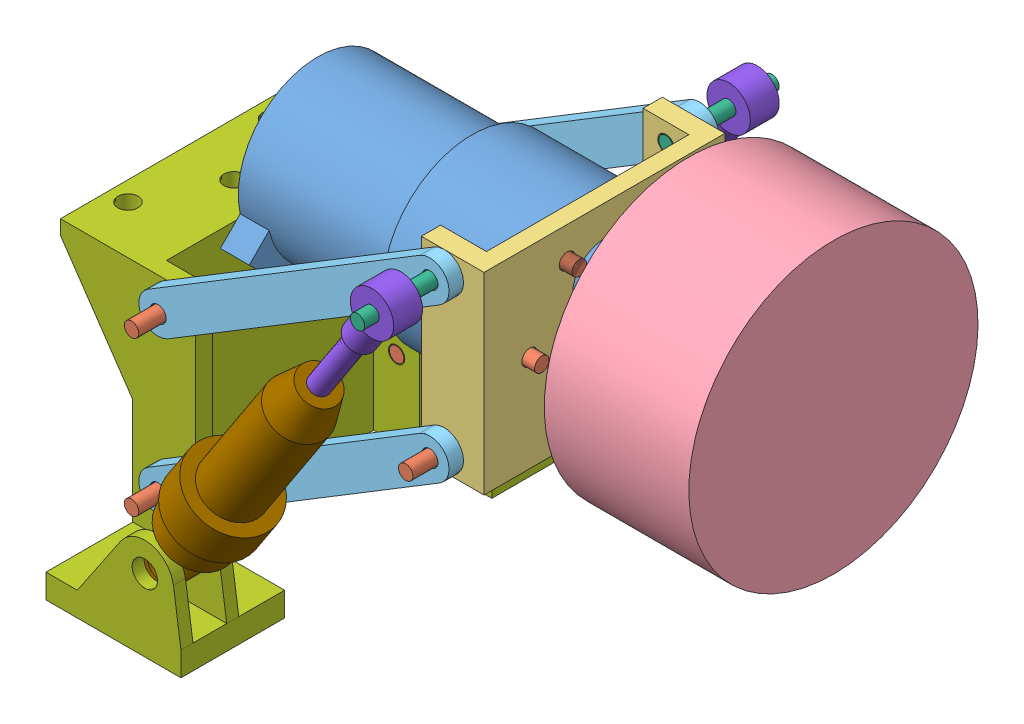
SolidWorks assembly 悬挂, configuration 默认. Lengths in mm.
Overall size (135.39 111.77 91).
29 component instances, 9 part files, 55 mates.
Components (placement in the parent):
- 37mm电机简化-1: 37mm电机简化 [默认] at (-59.3265 -45.8571 59.5689) size (74 38.77 38.72)
- M3-12螺丝简化-1: M3-12螺丝简化 [默认] at (-29.3265 -32.4337 67.3189) x (0 -0.670564 0.741852) z (-1 0 0) size (3 3 12)
- 双叉连接-1: 双叉连接 [默认] at (-36.8265 -45.8571 59.5689) x (0 0 1) z (1 0 0) size (50 40 13)
- 麦轮简化-1: 麦轮简化 [默认] at (15.6735 -38.8571 59.5689) x (0 0.939245 -0.343247) z (0 0.343247 0.939245) size (60 45 60)
- 双叉连杆-1: 双叉连杆 [默认] at (-68.2713 -79.0051 34.5689) x (0.854387 0.519637 0) z (-0.519637 0.854387 0) size (74 3 8)
- M3-12螺丝简化-17: M3-12螺丝简化 [默认] at (-41.3265 -59.2805 51.8189) x (0 0 -1) z (1 0 0) size (3 3 12)
- M3-12螺丝简化-18: M3-12螺丝简化 [默认] at (-41.3265 -32.4337 51.8189) x (0 0 -1) z (1 0 0) size (3 3 12)
- M3-12螺丝简化-19: M3-12螺丝简化 [默认] at (-41.3265 -45.8571 44.0689) x (0 0 -1) z (1 0 0) size (3 3 12)
- M3-12螺丝简化-20: M3-12螺丝简化 [默认] at (-41.3265 -45.8571 75.0689) x (0 0 -1) z (1 0 0) size (3 3 12)
- M3-12螺丝简化-21: M3-12螺丝简化 [默认] at (-41.3265 -32.4337 67.3189) x (0 0 -1) z (1 0 0) size (3 3 12)
- 双叉连杆-2: 双叉连杆 [默认] at (-68.2713 -79.0051 87.5689) x (0.854387 0.519637 0) z (-0.519637 0.854387 0) size (74 3 8)
- 双叉连杆-3: 双叉连杆 [默认] at (-68.2713 -47.0051 87.5689) x (0.854387 0.519637 0) z (-0.519637 0.854387 0) size (74 3 8)
- 双叉连杆-4: 双叉连杆 [默认] at (-68.2713 -47.0051 34.5689) x (0.854387 0.519637 0) z (-0.519637 0.854387 0) size (74 3 8)
- M3-12螺丝简化-23: M3-12螺丝简化 [默认] at (-40.0765 -61.8571 26.5689) x (0.912289 -0.409547 0) z (0 0 1) size (3 3 12)
- M3-12螺丝简化-24: M3-12螺丝简化 [默认] at (-40.0765 -61.8571 80.5689) size (3 3 12)
- M3-12螺丝简化-27: M3-12螺丝简化 [默认] at (-29.3265 -59.2805 67.3189) x (0 0 1) z (-1 0 0) size (3 3 12)
- M3-16螺丝简化-1: M3-16螺丝简化 [默认] at (-40.0765 -29.8571 16.5689) size (3 3 22)
- M3-16螺丝简化-2: M3-16螺丝简化 [默认] at (-40.0765 -29.8571 80.5689) x (0.99844 -0.055842 0) z (0 0 1) size (3 3 22)
- 弹簧支架-1: 弹簧支架 [默认] at (-99.716 -80.1532 59.5689) x (0 0 1) z (-1 0 0) size (86 52 43)
- M3-12螺丝简化-28: M3-12螺丝简化 [默认] at (-96.466 -64.1532 26.0689) size (3 3 12)
- M3-12螺丝简化-29: M3-12螺丝简化 [默认] at (-96.466 -96.1532 26.0689) size (3 3 12)
- M3-12螺丝简化-30: M3-12螺丝简化 [默认] at (-96.466 -96.1532 81.0689) size (3 3 12)
- M3-12螺丝简化-31: M3-12螺丝简化 [默认] at (-96.466 -64.1532 81.0689) size (3 3 12)
- 避震器简化-1: 避震器简化 [默认] at (55.1031 -55.4246 67.9345) size (59.67 81.53 17) (flexible)
  - 避震器简化-1: 避震器简化 [默认] at (-106.1486 8.8438 -45.3656) x (0 0 1) z (-0.836182 0.548453 0) size (6 39.5 9)
  - 避震器下简化-1: 避震器下简化 [默认] at (-103.6697 12.6232 -45.3656) x (0 0 1) z (-0.836182 0.548453 0) size (17 59 17)
- 避震器简化-2: 避震器简化 [默认] at (55.1031 -55.4246 141.9345) size (59.67 81.53 17) (flexible)
  - 避震器简化-1: 避震器简化 [默认] at (-106.1486 8.8438 -45.3656) x (0 0 1) z (-0.836182 0.548453 0) size (6 39.5 9)
  - 避震器下简化-1: 避震器下简化 [默认] at (-103.6697 12.6232 -45.3656) x (0 0 1) z (-0.836182 0.548453 0) size (17 59 17)
Mates (geometry in assembly coordinates):
- 同心1: concentric anti-aligned: circle of 37mm电机简化-1; circle of 双叉连接-1
- 同心2: concentric anti-aligned: circle of 37mm电机简化-1; circle of 双叉连接-1
- 同心3: concentric anti-aligned: circle of 37mm电机简化-1; circle of M3-12螺丝简化-1
- 重合3: coincident anti-aligned: plane of 37mm电机简化-1 through (-41.3265 -32.4337 67.3189) normal (1 0 0); plane of M3-12螺丝简化-1 through (-41.3265 -32.4337 67.3189) normal (-1 0 0)
- 重合18: coincident anti-aligned: plane of 37mm电机简化-1 through (-41.3265 -32.4337 51.8189) normal (1 0 0); plane of M3-12螺丝简化-17 through (-41.3265 -59.2805 51.8189) normal (-1 0 0)
- 同心9: concentric anti-aligned: circle of 双叉连接-1; circle of M3-12螺丝简化-17
- 重合19: coincident anti-aligned: plane of 37mm电机简化-1 through (-41.3265 -45.8571 75.0689) normal (1 0 0); plane of M3-12螺丝简化-21 through (-41.3265 -32.4337 67.3189) normal (-1 0 0)
- 重合20: coincident anti-aligned: plane of 37mm电机简化-1 through (-41.3265 -59.2805 67.3189) normal (1 0 0); plane of M3-12螺丝简化-21 through (-41.3265 -32.4337 67.3189) normal (-1 0 0)
- 重合22: coincident aligned: plane of M3-12螺丝简化-18 through (-41.3265 -32.4337 51.8189) normal (-1 0 0); plane of M3-12螺丝简化-19 through (-41.3265 -45.8571 44.0689) normal (-1 0 0)
- 重合24: coincident aligned: plane of M3-12螺丝简化-19 through (-41.3265 -45.8571 44.0689) normal (-1 0 0); plane of M3-12螺丝简化-20 through (-41.3265 -45.8571 75.0689) normal (-1 0 0)
- 重合25: coincident anti-aligned: plane of 37mm电机简化-1 through (-41.3265 -45.8571 75.0689) normal (1 0 0); plane of M3-12螺丝简化-18 through (-41.3265 -32.4337 51.8189) normal (-1 0 0)
- 同心10: concentric anti-aligned: circle of 双叉连接-1; circle of M3-12螺丝简化-20
- 同心11: concentric anti-aligned: circle of 双叉连接-1; circle of M3-12螺丝简化-19
- 同心12: concentric anti-aligned: circle of 双叉连接-1; circle of M3-12螺丝简化-18
- 同心13: concentric anti-aligned: circle of 双叉连接-1; circle of M3-12螺丝简化-21
- 同心15: concentric anti-aligned: circle of 37mm电机简化-1; circle of 麦轮简化-1
- 重合30: coincident anti-aligned: plane of 37mm电机简化-1 through (-29.3265 -38.8571 59.5689) normal (1 0 0); plane of 麦轮简化-1 through (-29.3265 -38.8571 59.5689) normal (-1 0 0)
- 重合31: coincident anti-aligned: plane of 双叉连接-1 through (-31.8265 -65.8571 34.5689) normal (0 0 -1); plane of 双叉连杆-1 through (-96.466 -96.1532 34.5689) normal (0 0 1)
- 同心19: concentric anti-aligned: circle of 双叉连接-1; circle of 双叉连杆-1
- 同心20: concentric anti-aligned: circle of 双叉连杆-1; circle of M3-12螺丝简化-23
- 同心21: concentric anti-aligned: circle of 双叉连接-1; circle of 双叉连杆-4
- 重合38: coincident anti-aligned: plane of 双叉连接-1 through (-31.8265 -65.8571 34.5689) normal (0 0 -1); plane of 双叉连杆-4 through (-96.466 -64.1532 34.5689) normal (0 0 1)
- 重合40: coincident aligned: plane of 双叉连杆-2 through (-96.466 -96.1532 84.5689) normal (0 0 -1); plane of 双叉连杆-3 through (-96.466 -64.1532 84.5689) normal (0 0 -1)
- 重合41: coincident anti-aligned: plane of 双叉连接-1 through (-31.8265 -65.8571 84.5689) normal (0 0 1); plane of 双叉连杆-3 through (-96.466 -64.1532 84.5689) normal (0 0 -1)
- 同心23: concentric anti-aligned: circle of 双叉连接-1; circle of 双叉连杆-3
- 同心24: concentric anti-aligned: circle of 双叉连接-1; circle of 双叉连杆-2
- 同心25: concentric anti-aligned: circle of 双叉连杆-2; circle of M3-12螺丝简化-24
- 重合46: coincident anti-aligned: plane of 37mm电机简化-1 through (-35.3265 -45.8571 59.5689) normal (1 0 0); plane of 双叉连接-1 through (-35.3265 -45.8571 59.5689) normal (-1 0 0)
- 重合47: coincident anti-aligned: circle of 37mm电机简化-1; circle of M3-12螺丝简化-27
- 同心27: concentric aligned: circle of 双叉连接-1; circle of M3-12螺丝简化-27
- 同心28: concentric anti-aligned: circle of 双叉连杆-3; circle of M3-16螺丝简化-2
- 同心29: concentric anti-aligned: circle of 双叉连杆-4; circle of M3-16螺丝简化-1
- 重合52: coincident aligned: plane of 双叉连接-1 through (-44.8265 -65.8571 80.5689) normal (0 0 -1); plane of M3-12螺丝简化-24 through (-40.0765 -61.8571 80.5689) normal (0 0 -1)
- 重合53: coincident aligned: plane of 双叉连接-1 through (-35.3265 -65.8571 38.5689) normal (0 0 1); plane of M3-12螺丝简化-23 through (-40.0765 -61.8571 38.5689) normal (0 0 1)
- 重合54: coincident aligned: plane of 双叉连接-1 through (-35.3265 -65.8571 38.5689) normal (0 0 1); plane of M3-16螺丝简化-1 through (-40.0765 -29.8571 38.5689) normal (0 0 1)
- 重合55: coincident aligned: plane of 双叉连接-1 through (-44.8265 -65.8571 80.5689) normal (0 0 -1); plane of M3-16螺丝简化-2 through (-40.0765 -29.8571 80.5689) normal (0 0 -1)
- 重合56: coincident anti-aligned: plane of 双叉连杆-4 through (-96.466 -64.1532 34.5689) normal (0 0 1); plane of 弹簧支架-1 through (-104.716 -60.1532 34.5689) normal (0 0 -1)
- 同心31: concentric anti-aligned: circle of 双叉连杆-4; circle of 弹簧支架-1
- 同心32: concentric anti-aligned: circle of 双叉连杆-1; circle of 弹簧支架-1
- 同心33: concentric anti-aligned: circle of 双叉连杆-2; circle of 弹簧支架-1
- 同心34: concentric anti-aligned: circle of 双叉连杆-3; circle of 弹簧支架-1
- 同心35: concentric anti-aligned: circle of 双叉连杆-3; circle of M3-12螺丝简化-31
- 重合62: coincident anti-aligned: plane of 弹簧支架-1 through (-91.716 -60.1532 81.0689) normal (0 0 -1); circle of M3-12螺丝简化-31
- 同心36: concentric anti-aligned: circle of 双叉连杆-2; circle of M3-12螺丝简化-30
- 重合63: coincident anti-aligned: plane of 弹簧支架-1 through (-91.716 -60.1532 81.0689) normal (0 0 -1); circle of M3-12螺丝简化-30
- 同心37: concentric anti-aligned: circle of 双叉连杆-4; circle of M3-12螺丝简化-28
- 重合64: coincident aligned: plane of 弹簧支架-1 through (-101.216 -60.1532 38.0689) normal (0 0 1); plane of M3-12螺丝简化-28 through (-96.466 -64.1532 38.0689) normal (0 0 1)
- 同心38: concentric anti-aligned: circle of 双叉连杆-1; circle of M3-12螺丝简化-29
- 重合65: coincident aligned: plane of 弹簧支架-1 through (-101.216 -60.1532 38.0689) normal (0 0 1); plane of M3-12螺丝简化-29 through (-96.466 -96.1532 38.0689) normal (0 0 1)
- 同心39: concentric anti-aligned: circle of 弹簧支架-1; circle of 避震器简化-1/避震器下简化-1
- 同心40: concentric aligned: circle of M3-16螺丝简化-1; circle of 避震器简化-1/避震器简化-1
- 距离1: distance = 0.5 mm anti-aligned: plane of 弹簧支架-1 through (-119.716 -72.9799 26.0689) normal (0 0 -1); plane of 避震器简化-1/避震器下简化-1 through (-84.216 -97.1532 25.5689) normal (0 0 1)
- 同心41: concentric anti-aligned: circle of 弹簧支架-1; circle of 避震器简化-2/避震器下简化-1
- 同心42: concentric aligned: circle of M3-16螺丝简化-2; circle of 避震器简化-2/避震器简化-1
- 距离3: distance = 0.5 mm anti-aligned: plane of 避震器简化-2/避震器下简化-1 through (-84.216 -97.1532 93.5689) normal (0 0 -1); plane of 弹簧支架-1 through (-119.716 -72.9799 93.0689) normal (0 0 1)
